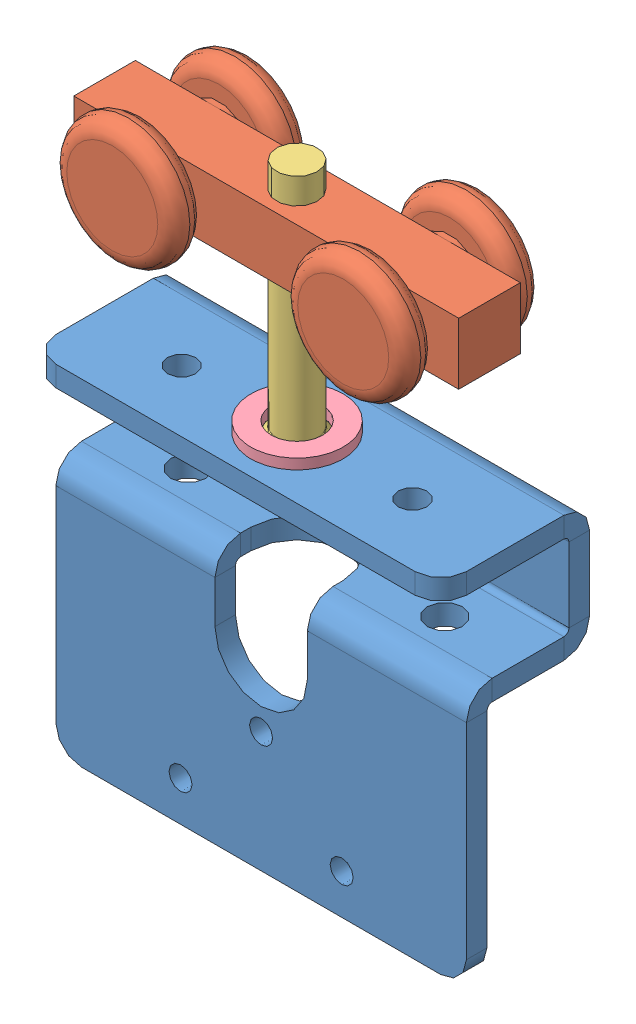
SolidWorks assembly B20-2K-, configuration Default. Lengths in mm.
Overall size (80 117.5 30.5).
4 component instances, 4 part files, 0 mates.
Components (placement in the parent):
- G2311(Default)--1: G2311(Default)- [Default] at origin size (80 70.5 29)
- G2029--1: G2029- [Default] at (0 59.5 -3) x (0 0 -1) z (1 0 0) size (27 24 75)
- G2316(B18.3.5M - 8 x 1.25 x 50 Socket FCHS  -- 28S)--1: G2316(B18.3.5M - 8 x 1.25 x 50 Socket FCHS  -- 28S)- [Default] at (0 20.5 -3) x (0 1 0) z (-0.922323 0 0.386419) size (50 15.5 15.5)
- BRB-10x18x2--1: BRB-10x18x2- [Default] at (0 24.5 -3) size (18 2 18)
